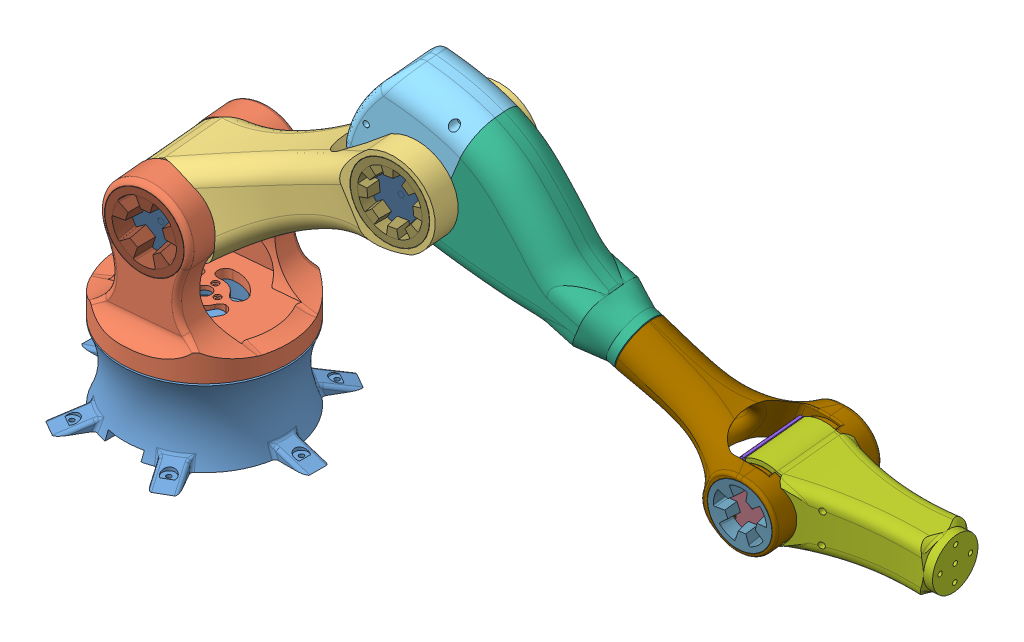
SolidWorks assembly Final Arm, configuration Default. Lengths in mm.
Overall size (483.2 274.12 138.73).
21 component instances, 14 part files, 48 mates.
Components (placement in the parent):
- rotation v3-2: rotation v3 [Default] at (42.8296 100.9612 24.2225) size (136.22 112.47 123.14)
- rotation top v4.2-3: rotation top v4.2 [Default] at (42.8296 146.9612 24.2225) x (0.091058 0 0.995846) z (-0.995846 0 0.091058) size (130.17 90.02 100)
- Lower Arm V1-2: Lower Arm V1 [Default] at (108.1879 247.8776 18.2463) x (0.871445 0.483978 -0.079683) z (0.481967 -0.87508 -0.04407) size (187.5 85.85 66.12)
- Lower Arm Bottom Cap V1-4: Lower Arm Bottom Cap V1 [Default] at (41.2412 211.3055 5.1881) x (0.871445 0.483978 -0.079683) z (0.481967 -0.87508 -0.04407) size (15 39 45.83)
- Upper Arm Back V2-3: Upper Arm Back V2 [Default] at (173.5463 284.176 12.27) x (0.927448 -0.364211 -0.084804) z (-0.362697 -0.931317 0.033164) size (56.73 40.84 85.27)
- Upper Arm Front V2-1: Upper Arm Front V2 [Default] at (173.5463 284.176 12.27) x (0.927448 -0.364211 -0.084804) z (-0.362697 -0.931317 0.033164) size (116.57 47.82 95.46)
- Arm Tip V1-1: Arm Tip V1 [Default] at (365.4471 208.8187 -5.1766) x (0.99561 -0.031783 -0.088038) z (0.087816 -0.008316 0.996102) size (102 40 50.65)
- Arm Tip  Cap V1-1: Arm Tip  Cap V1 [Default] at (365.4478 208.8392 -5.1765) x (0.99561 -0.031783 -0.088038) z (-0.087816 0.008316 -0.996102) size (10 34.64 39)
- Arm upper Rotation Long Ergo V1.2-1: Arm upper Rotation Long Ergo V1.2 [Default] at (218.4379 266.5469 8.1652) x (-0.087816 0.008316 -0.996102) z (-0.363496 -0.93128 0.024271) size (69.63 178.51 40.13)
- base side cap v1.2-1: base side cap v1.2 [Default] at (45.4521 211.5792 52.9029) x (0.704169 -0.707107 -0.064388) z (0.704169 0.707107 -0.064388) size (42.2 3.5 42.2)
- base side cap v1.2-2: base side cap v1.2 [Default] at (40.2071 211.5792 -4.4578) x (0 1 0) z (0.995846 0 -0.091058) size (42.2 3.5 42.2)
- Swag Element Base V1-1: Swag Element Base V1 [Default] at (40.2071 211.9612 -4.4578) x (-0.995846 0 0.091058) z (-0.091058 0 -0.995846) size (43.5 43.5 11.31)
- Swag Element Base V1-2: Swag Element Base V1 [Default] at (45.4521 211.9612 52.9029) x (0.995846 0 -0.091058) z (0.091058 0 0.995846) size (43.5 43.5 11.31)
- base side cap v1.2-3: base side cap v1.2 [Default] at (171.0422 284.176 -15.1157) x (0.871445 0.483978 -0.079683) z (0.481967 -0.87508 -0.04407) size (42.2 3.5 42.2)
- base side cap v1.2-4: base side cap v1.2 [Default] at (176.0504 284.176 39.6558) x (0.481967 -0.87508 -0.04407) z (0.871445 0.483978 -0.079683) size (42.2 3.5 42.2)
- Swag Element lower armV1-1: Swag Element lower armV1 [Default] at (171.0422 284.176 -15.1157) x (-0.995846 0 0.091058) z (-0.091058 0 -0.995846) size (43.5 43.5 7.75)
- Swag Element lower armV1-2: Swag Element lower armV1 [Default] at (176.0504 284.176 39.6558) x (-0.642433 -0.764087 0.058743) z (0.091058 0 0.995846) size (43.5 43.5 7.75)
- arm tip lid v1-1: arm tip lid v1 [Default] at (363.2605 209.0258 -29.9796) x (-0.740165 -0.669774 0.059661) z (-0.087816 0.008316 -0.996102) size (35 34.87 3)
- arm tip lid v1-2: arm tip lid v1 [Default] at (367.6162 208.6133 19.4271) x (0.653689 -0.754058 -0.063924) z (0.087816 -0.008316 0.996102) size (35 34.87 3)
- Swag Element Tip V1-1: Swag Element Tip V1 [Default] at (363.0849 209.0424 -31.9718) x (-0.740165 -0.669774 0.059661) z (-0.087816 0.008316 -0.996102) size (35.5 35.5 8.16)
- Swag Element Tip V1-2: Swag Element Tip V1 [Default] at (367.7918 208.5967 21.4193) x (0.763647 0.642654 -0.061958) z (0.087816 -0.008316 0.996102) size (35.5 35.5 8.16)
Mates (geometry in assembly coordinates):
- Distance1: distance = 1 mm anti-aligned: plane of rotation top v4.2-3 through (42.8296 146.9612 24.2225) normal (0 -1 0); plane of rotation v3-2 through (42.8296 145.9612 24.2225) normal (0 1 0)
- Concentric1: concentric aligned: circle of rotation v3-2; circle of rotation top v4.2-3
- Distance2: distance = 0.3 mm anti-aligned: plane of rotation top v4.2-3 through (69.5287 236.9612 41.6638) normal (-0.091058 0 -0.995846); plane of Lower Arm V1-2 through (44.6052 211.5792 43.6415) normal (0.091058 0 0.995846)
- Concentric2: concentric aligned: cylinder of rotation top v4.2-3 through (40.7535 211.5792 1.5173) axis (-0.091058 0 -0.995846) radius 4.8; circle of Lower Arm V1-2
- Distance4: distance = 0.1 mm anti-aligned: plane of Lower Arm V1-2 through (23.8318 223.4687 45.541) normal (-0.481967 0.87508 0.04407); plane of Lower Arm Bottom Cap V1-4 through (22.2851 223.9619 16.5615) normal (0.481967 -0.87508 -0.04407)
- Coincident14: coincident anti-aligned: plane of Lower Arm V1-2 through (107.3229 247.8776 8.7857) normal (-0.091058 0 -0.995846); plane of Lower Arm Bottom Cap V1-4 through (42.1153 211.3055 14.7482) normal (0.091058 0 0.995846)
- Coincident15: coincident anti-aligned: plane of Lower Arm V1-2 through (15.7035 234.3819 -8.4431) normal (-0.871445 -0.483978 0.079683); plane of Lower Arm Bottom Cap V1-4 through (25.0347 226.5163 45.8327) normal (0.871445 0.483978 -0.079683)
- Distance8: distance = 0.8 mm anti-aligned: plane of Lower Arm V1-2 through (209.1845 274.3984 28.8939) normal (-0.091058 0 -0.995846); plane of Upper Arm Back V2-3 through (224.549 311.526 26.6857) normal (0.091058 0 0.995846)
- Concentric6: concentric aligned: circle of Lower Arm V1-2; circle of Upper Arm Back V2-3
- Parallel2: parallel anti-aligned: plane of Upper Arm Back V2-3 through (184.3088 269.6411 23.336) normal (0.927448 -0.364211 -0.084804); plane of Upper Arm Front V2-1 through (205.5479 331.7726 -11.2233) normal (-0.927448 0.364211 0.084804)
- Parallel3: parallel anti-aligned: line of Upper Arm Back V2-3 through (189.1026 289.1988 -8.2317) axis (0.362697 0.931317 -0.033164); line of Upper Arm Front V2-1 through (197.0689 309.6542 -8.9601) axis (-0.362697 -0.931317 0.033164)
- Concentric7: concentric aligned: circle of Upper Arm Back V2-3; circle of Upper Arm Front V2-1
- Coincident20: coincident anti-aligned: plane of Upper Arm Back V2-3 through (184.3088 269.6411 23.336) normal (0.927448 -0.364211 -0.084804); plane of Upper Arm Front V2-1 through (205.5479 331.7726 -11.2233) normal (-0.927448 0.364211 0.084804)
- Coincident29: coincident anti-aligned: plane of Arm Tip V1-1 through (353.8599 227.3384 -29.3134) normal (-0.99561 0.031783 0.088038); plane of Arm Tip  Cap V1-1 through (356.3703 196.041 10.3748) normal (0.99561 -0.031783 -0.088038)
- Coincident31: coincident aligned: plane of Arm Tip V1-1 through (367.1595 208.6566 14.2474) normal (0.087816 -0.008316 0.996102); plane of Arm Tip  Cap V1-1 through (367.1602 208.6771 14.2475) normal (0.087816 -0.008316 0.996102)
- Distance14: distance = 0.3 mm anti-aligned: plane of Arm Tip  Cap V1-1 through (356.0943 193.202 15.0939) normal (0.032391 0.99946 0.005488); plane of Arm Tip V1-1 through (354.7102 193.5463 15.2188) normal (-0.032391 -0.99946 -0.005488)
- Distance15: distance = 0.5 mm anti-aligned: plane of Upper Arm Front V2-1 through (281.5043 241.7806 2.3985) normal (0.927448 -0.364211 -0.084804); plane of Arm upper Rotation Long Ergo V1.2-1 through (281.9681 241.5985 2.3561) normal (-0.927448 0.364211 0.084804)
- Concentric8: concentric aligned: circle of Upper Arm Front V2-1; circle of Arm upper Rotation Long Ergo V1.2-1
- Concentric9: concentric aligned: circle of Arm Tip V1-1; circle of Arm upper Rotation Long Ergo V1.2-1
- Distance16: distance = 0.4 mm anti-aligned: plane of Arm Tip V1-1 through (363.7347 208.9809 -24.6006) normal (-0.087816 0.008316 -0.996102); plane of Arm upper Rotation Long Ergo V1.2-1 through (223.9691 285.3372 -12.043) normal (0.087816 -0.008316 0.996102)
- Coincident34: coincident anti-aligned: plane of rotation top v4.2-3 through (45.27 211.9612 50.9112) normal (0.091058 0 0.995846); plane of base side cap v1.2-1 through (45.27 211.5792 50.9112) normal (-0.091058 0 -0.995846)
- Concentric10: concentric aligned: circle of rotation top v4.2-3; circle of base side cap v1.2-1
- Parallel4: parallel anti-aligned: line of rotation top v4.2-3 through (59.1117 229.0142 49.6455) axis (-0.704169 -0.707107 0.064388); line of base side cap v1.2-1 through (57.4511 227.1639 51.8057) axis (0.704169 0.707107 -0.064388)
- Coincident36: coincident anti-aligned: plane of rotation top v4.2-3 through (40.3892 211.9612 -2.4661) normal (-0.091058 0 -0.995846); plane of base side cap v1.2-2 through (40.3892 211.5792 -2.4661) normal (0.091058 0 0.995846)
- Concentric11: concentric anti-aligned: circle of rotation top v4.2-3; circle of base side cap v1.2-2
- Parallel5: parallel aligned: line of base side cap v1.2-2 through (59.6659 214.0792 -6.2371) axis (0.995846 0 -0.091058); line of rotation top v4.2-3 through (60.3196 209.0792 -4.2885) axis (0.995846 0 -0.091058)
- Coincident39: coincident anti-aligned: plane of base side cap v1.2-2 through (40.2071 211.5792 -4.4578) normal (-0.091058 0 -0.995846); plane of Swag Element Base V1-1 through (40.2071 211.9612 -4.4578) normal (0.091058 0 0.995846)
- Concentric12: concentric anti-aligned: cylinder of rotation top v4.2-3 through (40.3892 211.9612 -2.4661) axis (-0.091058 0 -0.995846) radius 22; cylinder of Swag Element Base V1-1 through (39.2055 211.9612 -15.4121) axis (0.091058 0 0.995846) radius 21.75
- Coincident40: coincident anti-aligned: plane of base side cap v1.2-1 through (45.4521 211.5792 52.9029) normal (0.091058 0 0.995846); plane of Swag Element Base V1-2 through (45.4521 211.9612 52.9029) normal (-0.091058 0 -0.995846)
- Concentric13: concentric anti-aligned: cylinder of rotation top v4.2-3 through (45.27 211.9612 50.9112) axis (0.091058 0 0.995846) radius 22; cylinder of Swag Element Base V1-2 through (46.4537 211.9612 63.8572) axis (-0.091058 0 -0.995846) radius 21.75
- Coincident41: coincident anti-aligned: plane of Lower Arm V1-2 through (171.2243 284.176 -13.124) normal (-0.091058 0 -0.995846); plane of base side cap v1.2-3 through (171.2243 284.176 -13.124) normal (0.091058 0 0.995846)
- Concentric14: concentric aligned: circle of Lower Arm V1-2; circle of base side cap v1.2-3
- Coincident42: coincident anti-aligned: plane of Lower Arm V1-2 through (175.8683 284.176 37.6641) normal (0.091058 0 0.995846); plane of base side cap v1.2-4 through (175.8683 284.176 37.6641) normal (-0.091058 0 -0.995846)
- Concentric15: concentric anti-aligned: circle of Lower Arm V1-2; circle of base side cap v1.2-4
- Parallel6: parallel aligned: line of Lower Arm V1-2 through (156.5447 287.1585 39.431) axis (-0.957007 0.276551 0.087507); line of base side cap v1.2-4 through (156.662 287.1773 41.4286) axis (-0.957007 0.276551 0.087507)
- Parallel7: parallel anti-aligned: line of Lower Arm V1-2 through (191.4536 275.7288 -14.9738) axis (-0.957007 0.276551 0.087507); line of base side cap v1.2-3 through (189.0536 276.3697 -16.7627) axis (0.957007 -0.276551 -0.087507)
- Coincident46: coincident anti-aligned: plane of base side cap v1.2-3 through (171.0422 284.176 -15.1157) normal (-0.091058 0 -0.995846); plane of Swag Element lower armV1-1 through (171.0422 284.176 -15.1157) normal (0.091058 0 0.995846)
- Concentric18: concentric aligned: circle of Lower Arm V1-2; circle of Swag Element lower armV1-1
- Concentric19: concentric anti-aligned: cylinder of Lower Arm V1-2 through (175.8683 284.176 37.6641) axis (0.091058 0 0.995846) radius 22; cylinder of Swag Element lower armV1-2 through (176.7333 284.176 47.1246) axis (-0.091058 0 -0.995846) radius 21.75
- Coincident48: coincident anti-aligned: plane of base side cap v1.2-4 through (176.0504 284.176 39.6558) normal (0.091058 0 0.995846); plane of Swag Element lower armV1-2 through (176.0504 284.176 39.6558) normal (-0.091058 0 -0.995846)
- Coincident49: coincident anti-aligned: plane of Arm upper Rotation Long Ergo V1.2-1 through (363.2605 209.0258 -29.9796) normal (-0.087816 0.008316 -0.996102); plane of arm tip lid v1-1 through (363.2605 209.0258 -29.9796) normal (0.087816 -0.008316 0.996102)
- Concentric21: concentric aligned: circle of Arm upper Rotation Long Ergo V1.2-1; circle of arm tip lid v1-1
- Coincident50: coincident anti-aligned: plane of Arm upper Rotation Long Ergo V1.2-1 through (367.6162 208.6133 19.4271) normal (0.087816 -0.008316 0.996102); plane of arm tip lid v1-2 through (367.6162 208.6133 19.4271) normal (-0.087816 0.008316 -0.996102)
- Concentric22: concentric anti-aligned: circle of Arm upper Rotation Long Ergo V1.2-1; circle of arm tip lid v1-2
- Coincident51: coincident anti-aligned: plane of arm tip lid v1-1 through (363.0849 209.0424 -31.9718) normal (-0.087816 0.008316 -0.996102); plane of Swag Element Tip V1-1 through (363.0849 209.0424 -31.9718) normal (0.087816 -0.008316 0.996102)
- Concentric23: concentric anti-aligned: circle of arm tip lid v1-1; circle of Swag Element Tip V1-1
- Coincident57: coincident anti-aligned: plane of arm tip lid v1-2 through (367.7918 208.5967 21.4193) normal (0.087816 -0.008316 0.996102); plane of Swag Element Tip V1-2 through (367.7918 208.5967 21.4193) normal (-0.087816 0.008316 -0.996102)
- Concentric24: concentric anti-aligned: circle of arm tip lid v1-2; circle of Swag Element Tip V1-2
